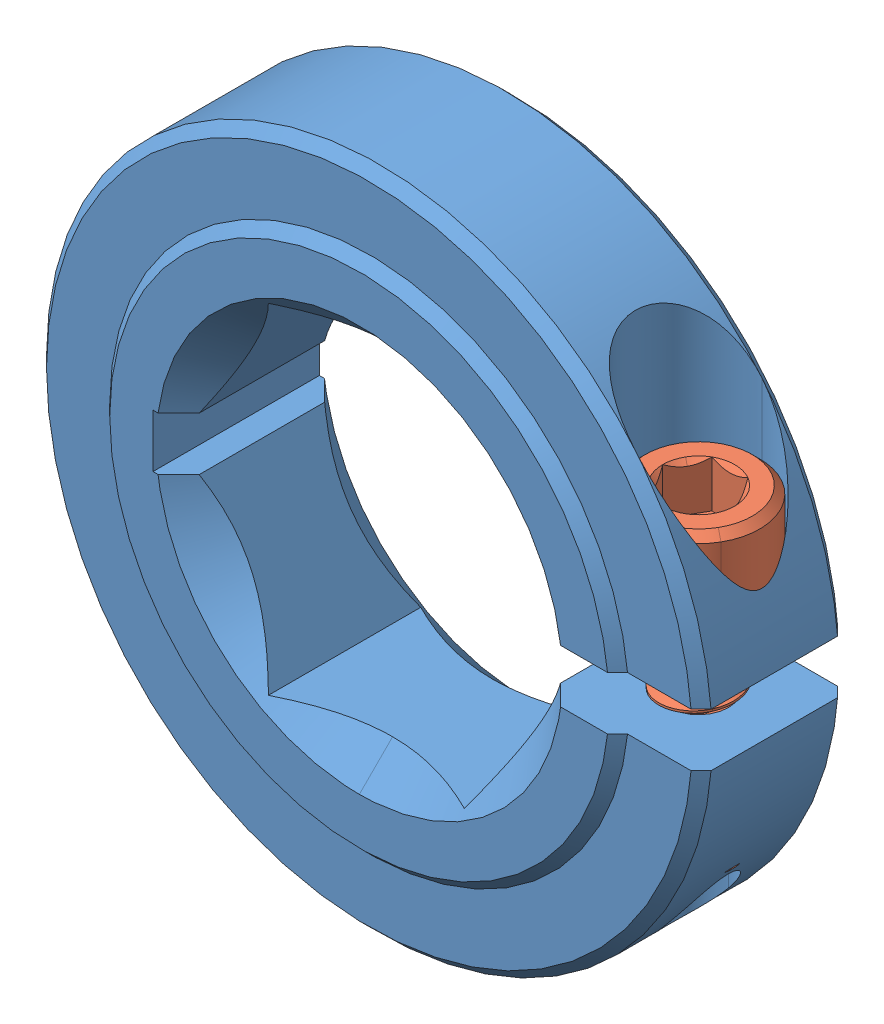
SolidWorks assembly am-1635 500Hex Thin Collar Clamp (1 Part).STEP, configuration Default. Lengths in mm.
Overall size (25.65 25.4 6.35).
2 component instances, 2 part files, 0 mates.
Components (placement in the parent):
- 500Hex Thin Collar Clamp Body v2.STEP-1: 500Hex Thin Collar Clamp Body v2.STEP [Default] at (-14.8913 -3.7428 7.2365) size (25.36 25.4 6.35)
- 4-40 x 0.375 SHCS with threads_91251A108.STEP-1: 4-40 x 0.375 SHCS with threads_91251A108.STEP [Default] at (-5.1154 -10.3468 10.4115) x (0.866025 0 0.5) z (0 -1 0) size (4.65 4.65 12.38)
